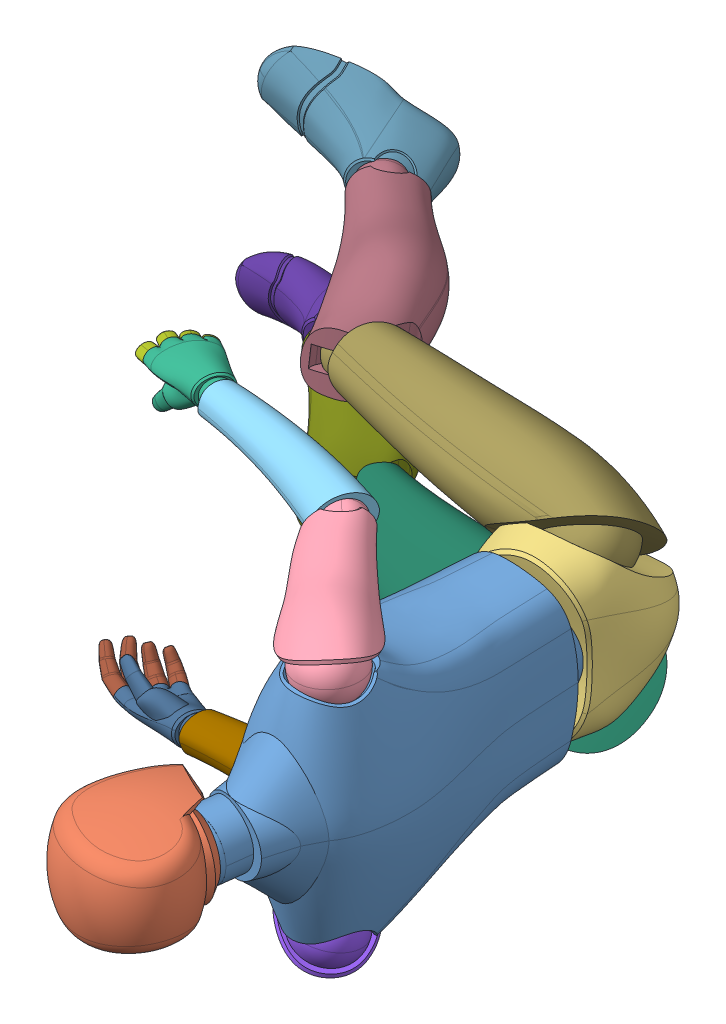
SolidWorks assembly .....Articulated_Dummy, configuration Default. Lengths in mm.
Overall size (1080.62 622.28 1340.25).
19 component instances, 17 part files, 18 mates.
Components (placement in the parent):
- Torso-1: .....Torso [Default] at origin size (276.17 406.18 676.75)
- Head-1: .....Head [Default] at (272.4966 0 13.9002) x (0.984808 0 0.173648) z (-0.173648 0 0.984808) size (223.51 154.11 248.99)
- Pelvis-1: .....Pelvis [Default] at (-175.9416 -0.0047 21.1469) x (0.984808 0 -0.173648) z (0.173648 0 0.984808) size (220.9 294.19 237.82)
- UpperArm_R-1: .....UpperArm_R [Default] at (-967.4121 -31.8704 494.9868) x (0.686668 0.032226 -0.726256) z (0.725991 0.021461 0.68737) size (145.29 112.21 352.1)
- LowerArm_R-1: .....LowerArm_R [Default] at (-1163.8165 -131.5552 990.6603) x (0.282282 -0.015764 -0.959202) z (0.953344 0.116147 0.278649) size (97.1 110.82 304.02)
- Hand_R-1: .....Hand_R [Default] at (-1071.8641 -48.9337 667.7427) x (0.586634 0.138363 -0.797945) z (0.805428 0.00317 0.592685) size (143.51 200.25 239.15)
  - Hand_R-1: .....Hand_R [Default] at origin size (143.51 200.25 232.94)
  - Fingers_R-1: .....Fingers_R [Default] at origin size (103.08 62.21 73.67)
- UpperArm_L-1: .....UpperArm_L [Default] at (-963.6086 40.2091 492.5524) x (0.655397 -0.202373 -0.727667) z (0.740186 -0.019578 0.672117) size (149.95 126.7 354.11)
- LowerArm_L-1: .....LowerArm_L [Default] at (-1215.8864 -1.0102 1100.795) x (0.200712 0.118224 -0.972491) z (0.979571 -0.01162 0.200761) size (97.1 110.82 304.02)
- Hand_L-1: .....Hand_L [Default] at (-1163.1688 -95.7629 792.4915) x (0.487614 -0.083042 -0.869101) z (0.870629 0.120485 0.476958) size (143.54 200.25 239.15)
  - Hand_L-1: .....Hand_L [Default] at origin size (143.54 200.25 232.94)
  - Fingers_L-1: .....Fingers_L [Default] at origin size (103.08 62.28 73.68)
- UpperLeg_R-1: .....UpperLeg_R [Default] at (-874.2977 48.5468 874.3966) x (0.108908 -0.602397 -0.790732) z (0.990819 0.001682 0.135184) size (212.64 165.47 563.01)
- LowerLeg_R-1: .....LowerLeg_R [Default] at (-712.3034 -40.8146 511.4118) x (0.771505 0.113631 -0.625994) z (0.620305 0.084374 0.77981) size (159.05 194.06 506.09)
- Foot_R-1: .....Foot_R [Default] at (-721.4345 -28.8172 498.7546) x (0.899051 -0.06744 -0.432619) z (0.434787 0.020963 0.900289) size (250.01 160.41 191.51)
- UpperLeg_L-1: .....UpperLeg_L [Default] at (-872.8456 -21.2577 898.3064) x (0.106044 0.59845 -0.794111) z (0.99355 -0.031522 0.108922) size (212.64 165.47 563.01)
- LowerLeg_L-1: .....LowerLeg_L [Default] at (-745.7676 -14.2143 531.1085) x (0.689228 -0.309105 -0.655301) z (0.704606 0.075229 0.7056) size (159.05 194.91 471.32)
- Foot_L-1: .....Foot_L [Default] at (-717.1717 -4.9666 523.6228) x (0.96643 -0.093697 -0.239235) z (0.236502 -0.039427 0.970831) size (250.8 160.43 191.19)
Mates (geometry in assembly coordinates):
- Coincident1: coincident: point of Torso-1; point of Head-1
- Parallel1: parallel aligned: plane of Head-1 through (272.4966 0 13.9002) normal (0 1 0)
- LimitAngle1: limit planar angle = 0.174533 rad aligned: plane of Head-1 through (272.4966 0 13.9002) normal (-0.173648 0 0.984808)
- Coincident5: coincident: point of Torso-1; point of Pelvis-1
- Parallel3: parallel aligned: plane of Pelvis-1 through (-175.9416 -0.0047 21.1469) normal (0 1 0)
- LimitAngle2: limit planar angle = 0.174533 rad aligned: plane of Pelvis-1 through (-175.9416 -0.0047 21.1469) normal (0.173648 0 0.984808); plane of Torso-1 through (0 0 0) normal (0 0 1)
- Coincident6: coincident: point of UpperArm_R-1; point of Torso-1
- Coincident7: coincident: point of UpperArm_R-1; point of LowerArm_R-1
- Coincident8: coincident: point of LowerArm_R-1; point of Hand_R-1
- Coincident9: coincident: point of UpperArm_L-1; point of Torso-1
- Coincident10: coincident: point of UpperArm_L-1; point of LowerArm_L-1
- Coincident11: coincident: point of LowerArm_L-1; point of Hand_L-1
- Coincident12: coincident: point of UpperLeg_R-1; point of Pelvis-1
- Coincident13: coincident: point of LowerLeg_R-1; point of UpperLeg_R-1
- Coincident14: coincident: point of LowerLeg_R-1; point of Foot_R-1
- Coincident15: coincident: point of Pelvis-1; point of UpperLeg_L-1
- Coincident16: coincident: point of LowerLeg_L-1; point of UpperLeg_L-1
- Coincident17: coincident: point of LowerLeg_L-1; point of Foot_L-1
